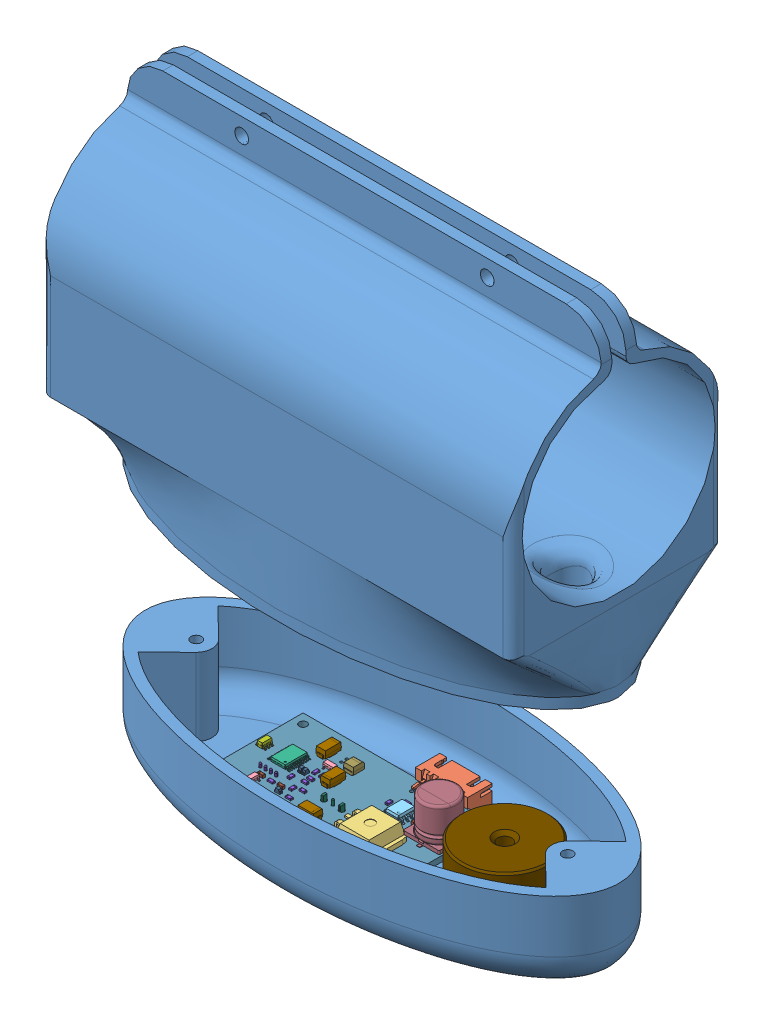
SolidWorks assembly box, configuration По умолчанию. Lengths in mm.
Overall size (153.69 167.9 77.4).
70 component instances, 19 part files, 8 mates.
Components (placement in the parent):
- box-1: box [По умолчанию] at origin size (153.69 27.34 77.4)
- pcb-1: pcb [По умолчанию] at (37 8 31) x (-1 0 0) z (0 1 0) size (56.35 34.62 18.7)
  - JST_XH_B5B-XH-A_1x05_P2.50mm_Vertical.step-1: JST_XH_B5B-XH-A_1x05_P2.50mm_Vertical.step [По умолчанию] at (27.178 -43.124 2.15) x (1 0 0) z (0 -1 0) size (14.9 5.75 10.4)
    - SOLID.step-1: SOLID.step [По умолчанию] at origin size (14.9 5.75 10.4)
  - TO-263-2.step-1: TO-263-2.step [По умолчанию] at (32.7 -21.5 1.65) x (-1 0 0) z (0 0 1) size (15 10 4.42)
    - SOLID-0.step-1: SOLID-0.step [По умолчанию] at origin size (15 10 4.42)
  - SOT-23.step-1: SOT-23.step [По умолчанию] at (62.484 -19.431 1.65) size (2.5 3 1.2)
    - SOLID-1.step-1: SOLID-1.step [По умолчанию] at origin size (2.5 3 1.2)
  - SOIC-8_3.9x4.9mm_P1.27mm.step-1: SOIC-8_3.9x4.9mm_P1.27mm.step [По умолчанию] at (33.02 -32.258 1.65) size (6 4.9 1.75)
    - SOLID-2.step-1: SOLID-2.step [По умолчанию] at origin size (6 4.9 1.75)
  - TSSOP-20_4.4x6.5mm_P0.65mm.step-1: TSSOP-20_4.4x6.5mm_P0.65mm.step [По умолчанию] at (62.484 -29.972 1.65) size (6.4 6.5 1.2)
    - SOLID-3.step-1: SOLID-3.step [По умолчанию] at origin size (6.4 6.5 1.2)
  - SOT-23-6.step-1: SOT-23-6.step [По умолчанию] at (69.426 -29.972 1.65) size (2.8 2.9 1.55)
    - SOLID-4.step-1: SOLID-4.step [По умолчанию] at origin size (2.8 2.9 1.55)
  - R_0603_1608Metric.step-1: R_0603_1608Metric.step [По умолчанию] at (54.356 -26.416 1.65) x (-1 0 0) z (0 0 1) size (1.6 0.8 0.45)
    - SOLID-5.step-1: SOLID-5.step [По умолчанию] at origin size (1.6 0.8 0.45)
  - R_0603_1608Metric.step-2: R_0603_1608Metric.step [По умолчанию] at (31.75 -35.814 1.65) x (-1 0 0) z (0 0 1) size (1.6 0.8 0.45)
    - SOLID-5.step-1: SOLID-5.step [По умолчанию] at origin size (1.6 0.8 0.45)
  - R_0603_1608Metric.step-3: R_0603_1608Metric.step [По умолчанию] at (34.67 -35.814 1.65) x (-1 0 0) z (0 0 1) size (1.6 0.8 0.45)
    - SOLID-5.step-1: SOLID-5.step [По умолчанию] at origin size (1.6 0.8 0.45)
  - R_0603_1608Metric.step-4: R_0603_1608Metric.step [По умолчанию] at (37.338 -33.337 1.65) x (0 1 0) z (0 0 1) size (1.6 0.8 0.45)
    - SOLID-5.step-1: SOLID-5.step [По умолчанию] at origin size (1.6 0.8 0.45)
  - R_0603_1608Metric.step-5: R_0603_1608Metric.step [По умолчанию] at (55.306 -30.48 1.65) x (0 1 0) z (0 0 1) size (1.6 0.8 0.45)
    - SOLID-5.step-1: SOLID-5.step [По умолчанию] at origin size (1.6 0.8 0.45)
  - R_0603_1608Metric.step-6: R_0603_1608Metric.step [По умолчанию] at (52.515 -24.003 1.65) size (1.6 0.8 0.45)
    - SOLID-5.step-1: SOLID-5.step [По умолчанию] at origin size (1.6 0.8 0.45)
  - R_0603_1608Metric.step-7: R_0603_1608Metric.step [По умолчанию] at (53.406 -30.48 1.65) x (0 1 0) z (0 0 1) size (1.6 0.8 0.45)
    - SOLID-5.step-1: SOLID-5.step [По умолчанию] at origin size (1.6 0.8 0.45)
  - R_0603_1608Metric.step-8: R_0603_1608Metric.step [По умолчанию] at (54.61 -23.178 1.65) x (0 -1 0) z (0 0 1) size (1.6 0.8 0.45)
    - SOLID-5.step-1: SOLID-5.step [По умолчанию] at origin size (1.6 0.8 0.45)
  - R_0603_1608Metric.step-9: R_0603_1608Metric.step [По умолчанию] at (52.769 -20.32 1.65) size (1.6 0.8 0.45)
    - SOLID-5.step-1: SOLID-5.step [По умолчанию] at origin size (1.6 0.8 0.45)
  - R_0603_1608Metric.step-10: R_0603_1608Metric.step [По умолчанию] at (57.7215 -25.781 1.65) x (0 -1 0) z (0 0 1) size (1.6 0.8 0.45)
    - SOLID-5.step-1: SOLID-5.step [По умолчанию] at origin size (1.6 0.8 0.45)
  - R_0603_1608Metric.step-11: R_0603_1608Metric.step [По умолчанию] at (54.356 -28.03 1.65) size (1.6 0.8 0.45)
    - SOLID-5.step-1: SOLID-5.step [По умолчанию] at origin size (1.6 0.8 0.45)
  - R_0603_1608Metric.step-12: R_0603_1608Metric.step [По умолчанию] at (59.436 -21.844 1.65) x (-1 0 0) z (0 0 1) size (1.6 0.8 0.45)
    - SOLID-5.step-1: SOLID-5.step [По умолчанию] at origin size (1.6 0.8 0.45)
  - SOT-23.step-2: SOT-23.step [По умолчанию] at (54.356 -33.616 1.65) x (0 -1 0) z (0 0 1) size (2.5 3 1.2)
    - SOLID-1.step-1: SOLID-1.step [По умолчанию] at origin size (2.5 3 1.2)
  - D_SMA.step-1: D_SMA.step [По умолчанию] at (50.546 -30.616 1.65) x (0 -1 0) z (0 0 1) size (5 2.7 2.22)
    - SOLID-6.step-1: SOLID-6.step [По умолчанию] at origin size (5 2.7 2.22)
  - D_SMA.step-2: D_SMA.step [По умолчанию] at (58.42 -37.211 1.65) x (0 1 0) z (0 0 1) size (5 2.7 2.22)
    - SOLID-6.step-1: SOLID-6.step [По умолчанию] at origin size (5 2.7 2.22)
  - D_SMA.step-3: D_SMA.step [По умолчанию] at (45.5 -19 1.65) size (5 2.7 2.22)
    - SOLID-6.step-1: SOLID-6.step [По умолчанию] at origin size (5 2.7 2.22)
  - LED_0603_1608Metric_Castellated.step-1: LED_0603_1608Metric_Castellated.step [По умолчанию] at (55.8295 -20.32 1.65) size (1.6 0.8 1.1)
    - SOLID-7.step-1: SOLID-7.step [По умолчанию] at origin size (1.6 0.8 1.1)
  - LED_0603_1608Metric_Castellated.step-2: LED_0603_1608Metric_Castellated.step [По умолчанию] at (56.642 -28.8425 1.65) x (0 -1 0) z (0 0 1) size (1.6 0.8 1.1)
    - SOLID-7.step-1: SOLID-7.step [По умолчанию] at origin size (1.6 0.8 1.1)
  - LED_0603_1608Metric_Castellated.step-3: LED_0603_1608Metric_Castellated.step [По умолчанию] at (57.7215 -28.8425 1.65) x (0 -1 0) z (0 0 1) size (1.6 0.8 1.1)
    - SOLID-7.step-1: SOLID-7.step [По умолчанию] at origin size (1.6 0.8 1.1)
  - C_0603_1608Metric.step-1: C_0603_1608Metric.step [По умолчанию] at (62.243 -21.844 1.65) size (1.6 0.8 0.8)
    - SOLID-8.step-1: SOLID-8.step [По умолчанию] at origin size (1.6 0.8 0.8)
  - CP_EIA-3528-21_Kemet-B.step-1: CP_EIA-3528-21_Kemet-B.step [По умолчанию] at (50.546 -36.576 1.65) x (0 1 0) z (0 0 1) size (3.5 2.8 2.1)
    - SOLID-9.step-1: SOLID-9.step [По умолчанию] at origin size (3.5 2.8 2.1)
  - C_0603_1608Metric.step-2: C_0603_1608Metric.step [По умолчанию] at (33.02 -28.702 1.65) size (1.6 0.8 0.8)
    - SOLID-8.step-1: SOLID-8.step [По умолчанию] at origin size (1.6 0.8 0.8)
  - C_0603_1608Metric.step-3: C_0603_1608Metric.step [По умолчанию] at (28.702 -32.118 1.65) x (0 -1 0) z (0 0 1) size (1.6 0.8 0.8)
    - SOLID-8.step-1: SOLID-8.step [По умолчанию] at origin size (1.6 0.8 0.8)
  - CP_Elec_10x10.5.step-1: CP_Elec_10x10.5.step [По умолчанию] at (22.479 -32.766 1.65) x (0 1 0) z (0 0 1) size (13.47 13.66 10.5)
    - SOLID-10.step-1: SOLID-10.step [По умолчанию] at origin size (13.47 13.66 10.5)
  - C_0603_1608Metric.step-4: C_0603_1608Metric.step [По умолчанию] at (56.642 -21.844 1.65) x (-1 0 0) z (0 0 1) size (1.6 0.8 0.8)
    - SOLID-8.step-1: SOLID-8.step [По умолчанию] at origin size (1.6 0.8 0.8)
  - COMPOUND.step-1: COMPOUND.step [По умолчанию] at origin size (55 28 1.6)
  - Magnet_conn-1: Magnet_conn [По умолчанию] at (45 -25 -0.7) x (0 -1 0) z (1 0 0) size (10 9.55 10)
  - ZH_02x01_1.5mm-1: ZH_02x01_1.5mm [По умолчанию] at (53.906 -37.548 0) x (0 1 0) z (-1 0 0) size (4.5 5.72 4.53)
  - ZH_04x01_1.5mm-1: ZH_04x01_1.5mm [По умолчанию] at (62.504 -23.632 0) x (1 0 0) z (0 1 0) size (7.5 7.2 3.5)
- magnit-1: magnit [По умолчанию] at (35 20 0) x (-0.837169 0 -0.546944) z (-0.546944 0 0.837169) size (25 20 25)
- in_os-1: in_os [По умолчанию] at (0 70.9968 0) x (0 0 -1) z (1 0 0) size (60.02 94.58 135.43)
Mates (geometry in assembly coordinates):
- Параллельность1: parallel anti-aligned: plane of box-1 through (64.4976 3 0.2222) normal (0 1 0); plane of pcb-1/COMPOUND.step-1 through (-7.5 8 1.5) normal (0 -1 0)
- Параллельность2: parallel aligned: plane of box-1 through (0 0 0) normal (0 0 1); plane of pcb-1/COMPOUND.step-1 through (-35 8 15.5) normal (0 0 1)
- Совпадение1: coincident anti-aligned: plane of box-1 through (17.2 8 12.7) normal (0 1 0); plane of pcb-1/COMPOUND.step-1 through (-7.5 8 1.5) normal (0 -1 0)
- Концентричный1: concentric aligned: cylinder of box-1 through (-8 0 6) axis (0 1 0) radius 6; cylinder of pcb-1/Magnet_conn-1 through (-8 3 6) axis (0 1 0) radius 5
- Совпадение5: coincident aligned: plane of box-1 through (0 0 0) normal (0 -1 0); plane of magnit-1 through (35 0 0) normal (0 -1 0)
- Концентричный2: concentric aligned: cylinder of box-1 through (35 0 0) axis (0 1 0) radius 12.5; cylinder of magnit-1 through (35 0 0) axis (0 1 0) radius 12.5
- Совпадение6: coincident anti-aligned: plane of in_os-1 through (0 70.9968 0) normal (0 0 -1)
- Совпадение7: coincident aligned: plane of in_os-1 through (0 70.9968 0) normal (1 0 0)
